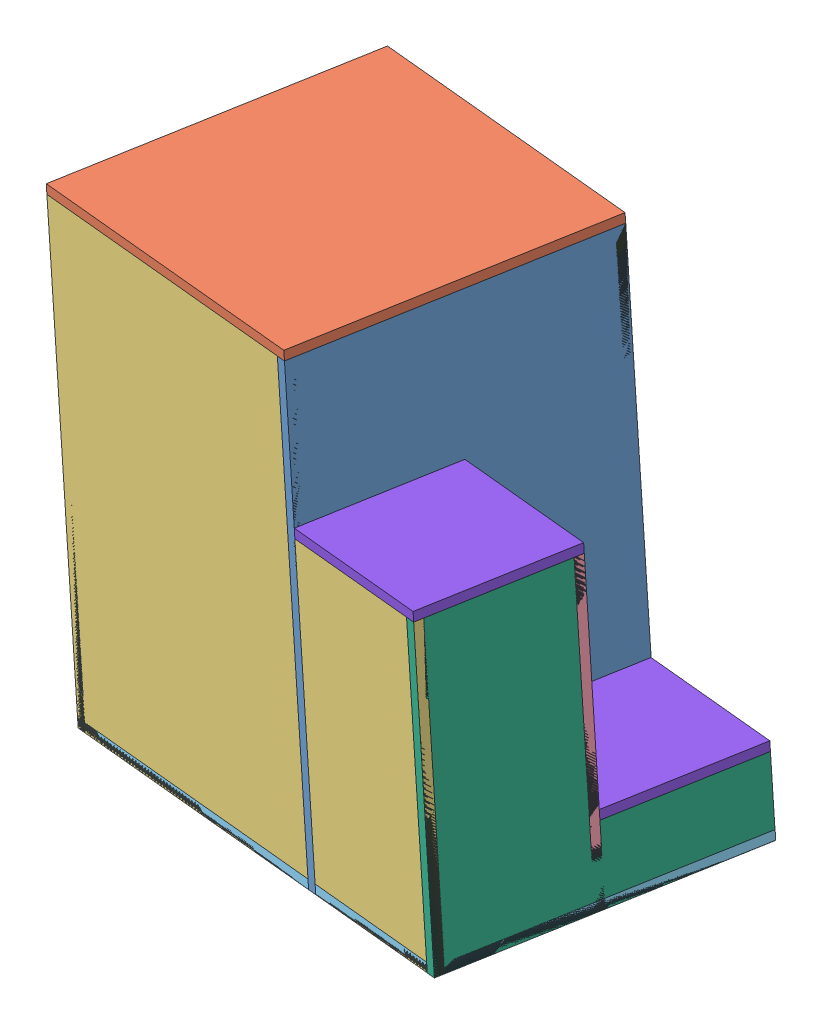
SolidWorks assembly Assembly1, configuration Default. Lengths in mm.
Overall size (355.48 325.11 253.8).
10 component instances, 8 part files, 22 mates.
Components (placement in the parent):
- PlantSide-2: PlantSide [Default] at (172.1519 -24.921 44.4149) x (0.174509 0.000068 -0.984656) z (0.980895 0.087306 0.173849) size (200 300 6)
- PlantSide-5: PlantSide [Default] at (-54.2192 -41.3509 248.504) x (-0.174509 -0.000068 0.984656) z (-0.980895 -0.087306 -0.173849) size (200 300 6)
- PlantCover-1: PlantCover [Default] at (62.8615 113.5324 125.0464) x (0.980895 0.087306 0.173849) z (-0.085979 0.996182 -0.015169) size (200 200 6)
- PlantFront-1: PlantFront [Default] at (160.4966 -22.6454 259.9191) x (0.980895 0.087306 0.173849) z (-0.174509 -0.000068 0.984656) size (300 300 6)
- ReservoirSExtraLong-1: ReservoirSExtraLong [Default] at (173.6465 -170.8227 166.7746) x (0.980895 0.087306 0.173849) z (-0.174509 -0.000068 0.984656) size (106 200 6)
- PlantBottom-3: PlantBottom [Default] at (80.5396 -179.3479 172.3863) x (0.980895 0.087306 0.173849) z (0.085979 -0.996182 0.015169) size (300 200 6)
- ReservoirFront-1: ReservoirFront [Default] at (247.488 -162.9774 263.8956) x (0.174543 -0.000319 -0.98465) z (0.980895 0.087306 0.173849) size (200 200 6)
- PlantBack-1: PlantBack [Default] at (161.1569 -48.12 69.1318) x (-0.980895 -0.087306 -0.173849) z (0.174543 -0.000319 -0.98465) size (300 300 6)
- ReservoirCover-2: ReservoirCover [Default] at (259.3153 -120.029 157.2143) x (0.980895 0.087306 0.173849) z (-0.174543 0.000319 0.98465) size (100 6 100)
- ReservoirCover-3: ReservoirCover [Default] at (228.9736 29.4396 253.3464) x (0.980895 0.087306 0.173849) z (-0.174509 -0.000068 0.984656) size (100 6 100)
Mates (geometry in assembly coordinates):
- Coincident30: coincident: point of PlantSide-5; plane of PlantFront-1 through (-69.1354 103.667 225.3239) normal (-0.980895 -0.087306 -0.173849)
- Coincident31: coincident: point of PlantSide-2; point of PlantFront-1
- Coincident46: coincident: point of PlantSide-5; point of PlantBottom-3
- Coincident48: coincident: point of PlantSide-5; point of PlantFront-1
- Coincident49: coincident: point of PlantSide-5; point of PlantCover-1
- Coincident50: coincident: point of PlantSide-5; point of PlantBottom-3
- Perpendicular2: perpendicular: plane of PlantSide-2 through (178.0373 -24.3972 45.458) normal (0.980895 0.087306 0.173849); plane of ReservoirSExtraLong-1 through (173.6465 -170.8227 166.7746) normal (0.174509 0.000068 -0.984656)
- Parallel9: parallel aligned: plane of PlantSide-2 through (127.0435 121.1283 260.0937) normal (-0.085979 0.996182 -0.015169); plane of PlantCover-1 through (62.3457 119.5095 124.9554) normal (-0.085979 0.996182 -0.015169)
- Coincident55: coincident: point of PlantFront-1; point of ReservoirFront-1
- Coincident56: coincident: point of ReservoirSExtraLong-1; point of PlantBottom-3
- Perpendicular3: perpendicular: plane of PlantSide-2 through (178.0373 -24.3972 45.458) normal (0.980895 0.087306 0.173849); plane of ReservoirSExtraLong-1 through (173.6465 -170.8227 166.7746) normal (0.174509 0.000068 -0.984656)
- Parallel11: parallel anti-aligned: plane of ReservoirSExtraLong-1 through (250.1347 30.2471 186.4379) normal (0.980895 0.087306 0.173849); plane of ReservoirFront-1 through (247.488 -162.9774 263.8956) normal (-0.980895 -0.087306 -0.173849)
- Coincident59: coincident aligned: plane of PlantBottom-3 through (268.3775 -168.9888 183.5638) normal (0.980895 0.087306 0.173849); plane of ReservoirFront-1 through (253.3733 -162.4536 264.9387) normal (0.980895 0.087306 0.173849)
- Coincident63: coincident: point of ReservoirFront-1; point of PlantBack-1
- Coincident64: coincident anti-aligned: line of ReservoirFront-1 through (285.8215 -169.0593 85.1759) axis (-0.085911 0.996181 -0.015552); line of PlantBack-1 through (281.526 -119.2503 84.3984) axis (0.085911 -0.996181 0.015552)
- Perpendicular4: perpendicular: plane of PlantSide-5 through (-60.1046 -41.8748 247.4609) normal (-0.980895 -0.087306 -0.173849); plane of PlantBack-1 through (161.1569 -48.12 69.1318) normal (-0.174543 0.000319 0.98465)
- Coincident74: coincident anti-aligned: plane of ReservoirFront-1 through (264.0717 -119.2184 182.8633) normal (-0.085911 0.996181 -0.015552); plane of ReservoirCover-2 through (259.3153 -120.029 157.2143) normal (0.085911 -0.996181 0.015552)
- Coincident75: coincident: point of PlantBack-1; point of ReservoirCover-2
- Parallel14: parallel aligned: plane of ReservoirFront-1 through (253.3733 -162.4536 264.9387) normal (0.980895 0.087306 0.173849); plane of ReservoirCover-2 through (281.0105 -113.2732 84.305) normal (0.980895 0.087306 0.173849)
- Coincident77: coincident: point of ReservoirSExtraLong-1; point of ReservoirCover-3
- Parallel15: parallel aligned: plane of ReservoirFront-1 through (253.3733 -162.4536 264.9387) normal (0.980895 0.087306 0.173849); plane of ReservoirCover-3 through (250.6659 36.2246 180.4389) normal (0.980895 0.087306 0.173849)
- Parallel16: parallel aligned: plane of ReservoirSExtraLong-1 through (146.1599 20.9927 168.0099) normal (-0.085979 0.996182 -0.015169); plane of ReservoirCover-3 through (228.4577 35.4167 253.2554) normal (-0.085979 0.996182 -0.015169)
